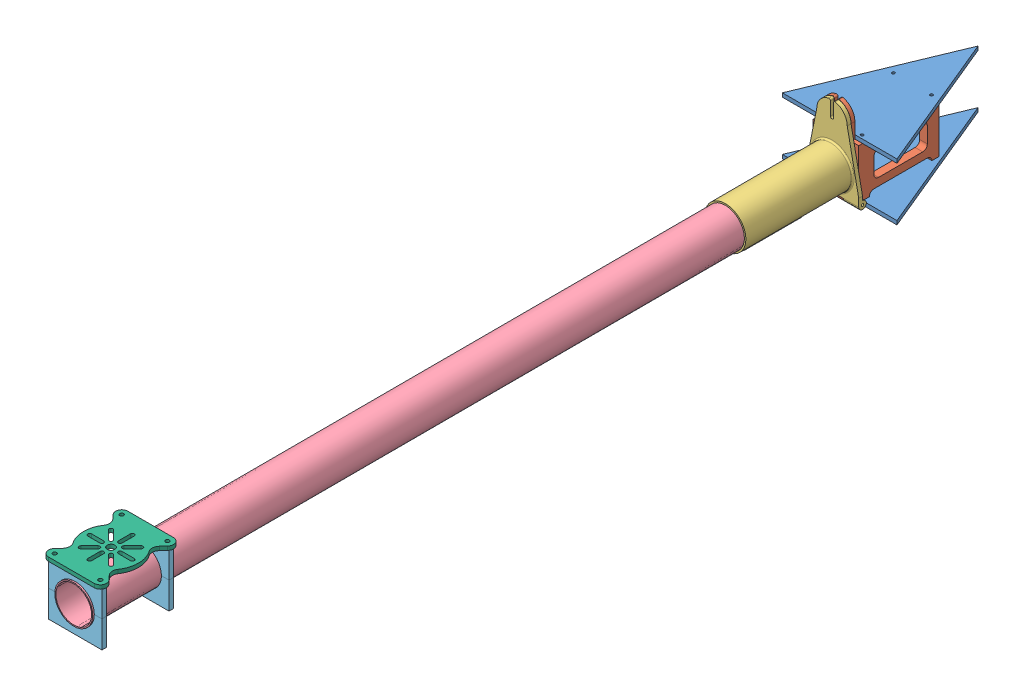
SolidWorks assembly ArmPosition, configuration Default. Lengths in mm.
Overall size (150.36 112.06 1189.62).
11 component instances, 6 part files, 9 mates.
Components (placement in the parent):
- NewHubPiece-1: NewHubPiece [Default] at (84.0761 108.6958 210.2555) size (150.36 5 181.5)
- 50mmHingeToBase-1: 50mmHingeToBase [Default] at (84.0761 143.6958 240.2555) size (60 109.55 110)
- NewHubPiece-2: NewHubPiece [Default] at (84.0761 178.6958 210.2555) size (150.36 5 181.5)
- 50mmArmAssembly-1: 50mmArmAssembly [Default] at (-28.9933 18.3519 140.7775) x (1 0 0) z (0 -0.001194 0.999999) size (76 110.85 1008)
  - 50mmHingeToArm-1: 50mmHingeToArm [Default] at (113.0694 125.4328 79.3641) size (70 110.85 150)
  - 50mmDiamDroneArm-1: 50mmDiamDroneArm [Default] at (113.0694 125.4328 79.3641) x (0.775778 0.631006 0) z (0 0 1) size (50 50 995)
  - 50mmTubeClamp-1: 50mmTubeClamp [Default] at (113.0694 125.4328 1064.3641) size (70 35.35 6)
  - 50mmTubeClamp-2: 50mmTubeClamp [Default] at (113.0694 125.4328 1064.3641) x (-1 0 0) z (0 0 1) size (70 35.35 6)
  - 50mmTubeClamp-3: 50mmTubeClamp [Default] at (113.0694 125.4328 976.3641) x (-1 0 0) z (0 0 1) size (70 35.35 6)
  - 50mmTubeClamp-4: 50mmTubeClamp [Default] at (113.0694 125.4328 976.3641) size (70 35.35 6)
  - 50mmMotorHolder-1: 50mmMotorHolder [Default] at (104.7598 160.7795 1001.9104) size (76 5 104)
Mates (geometry in assembly coordinates):
- Coincident1: coincident anti-aligned: plane of 50mmHingeToBase-1 through (119.0761 178.6958 110.2555) normal (0 1 0); plane of NewHubPiece-2 through (84.0761 178.6958 210.2555) normal (0 -1 0)
- Coincident2: coincident anti-aligned: plane of NewHubPiece-1 through (84.0761 113.6958 210.2555) normal (0 1 0); plane of 50mmHingeToBase-1 through (49.0761 113.6958 225.2555) normal (0 -1 0)
- Concentric5: concentric anti-aligned: cylinder of 50mmHingeToBase-1 through (134.0761 98.6958 225.2555) axis (-1 0 0) radius 6; cylinder of 50mmArmAssembly-1/50mmHingePin-1 through (14.0761 98.6958 225.2555) axis (1 0 0) radius 6
- Coincident3: coincident anti-aligned: plane of 50mmHingeToBase-1 through (99.0761 178.6958 210.2555) normal (1 0 0); plane of 50mmArmAssembly-1/50mmHingeToArm-1 through (99.0761 113.6958 215.2555) normal (-1 0 0)
- Concentric6: concentric anti-aligned: cylinder of 50mmHingeToBase-1 through (122.0761 113.6958 215.2555) axis (-1 0 0) radius 1.5; cylinder of 50mmArmAssembly-1/50mmHingeToArm-1 through (35.0761 113.6958 215.2555) axis (1 0 0) radius 1.5
- Concentric7: concentric aligned: cylinder of 50mmHingeToBase-1 through (59.0761 78.6958 205.7555) axis (0 1 0) radius 1.825; cylinder of NewHubPiece-2 through (59.0761 173.6958 205.7555) axis (0 1 0) radius 1.825
- Concentric8: concentric aligned: cylinder of 50mmHingeToBase-1 through (59.0761 78.6958 114.7555) axis (0 1 0) radius 1.825; cylinder of NewHubPiece-2 through (59.0761 173.6958 114.7555) axis (0 1 0) radius 1.825
- Concentric9: concentric aligned: cylinder of NewHubPiece-1 through (59.0761 103.6958 114.7555) axis (0 1 0) radius 1.825; cylinder of NewHubPiece-2 through (59.0761 173.6958 114.7555) axis (0 1 0) radius 1.825
- Concentric10: concentric aligned: cylinder of NewHubPiece-1 through (59.0761 103.6958 205.7555) axis (0 1 0) radius 1.825; cylinder of 50mmHingeToBase-1 through (59.0761 78.6958 205.7555) axis (0 1 0) radius 1.825
